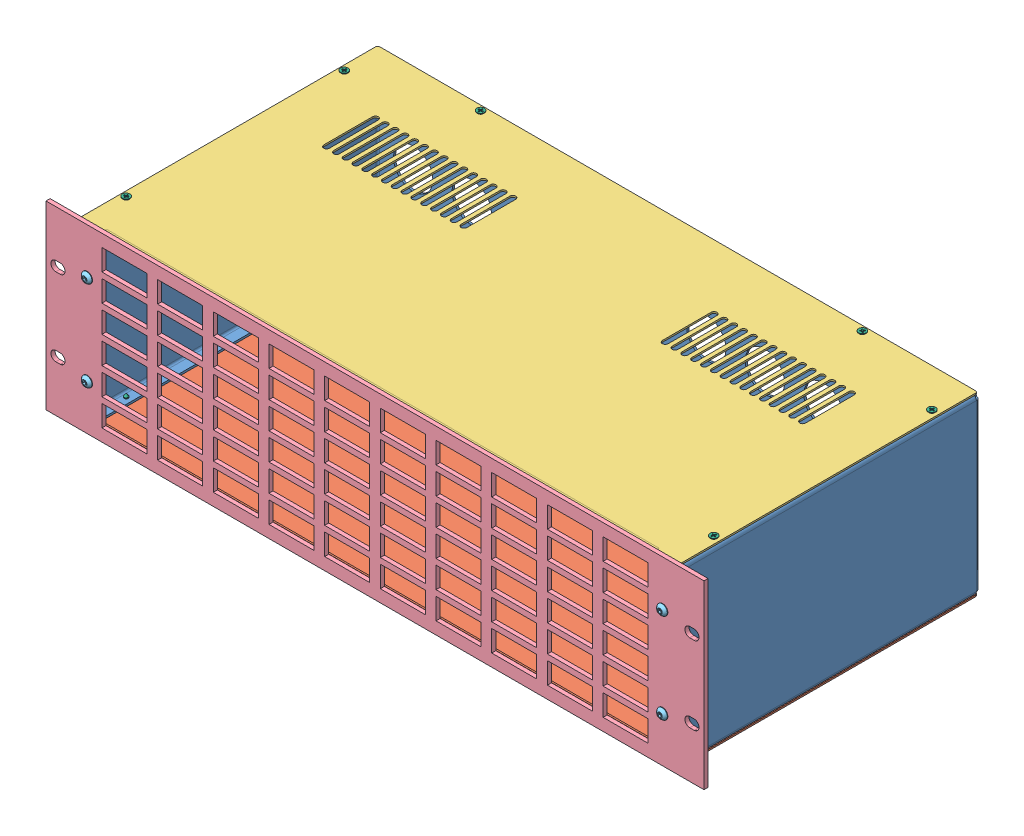
SolidWorks assembly Rack Wieland female, configuration R2100-3U. Lengths in mm.
Overall size (482.6 132.7 225.2).
20 component instances, 6 part files, 0 mates.
Components (placement in the parent):
- Frame 3U 10 presse-etoupes-1: Frame 3U 10 presse-etoupes [Défaut] at (0 0 -300) size (442 127 220)
- Penn Elcom-R2100-3U_R2100-R2110-Top-Base(R2100-005)-1: Penn Elcom-R2100-3U_R2100-R2110-Top-Base(R2100-005) [Default] at (0 -63.5 -80) x (-1 0 0) z (0 0 1) size (440 7.5 219)
- Penn Elcom-R2100-3U_R2100-R2110-Top-Base(R2100-006)-1: Penn Elcom-R2100-3U_R2100-R2110-Top-Base(R2100-006) [Default] at (0 63.5 -80) size (440 7.5 219)
- Rack 3U front panel 60x wieland female-1: Rack 3U front panel 60x wieland female [Default] at (0 0 -80) size (482.6 132.7 3)
- Penn Elcom-R2100-3U_02-012-10 (M4 x 10 Button Head)(02-012-10)-1: Penn Elcom-R2100-3U_02-012-10 (M4 x 10 Button Head)(02-012-10) [Default] at (211 -33 -74.8) x (0 0 -1) z (1 0 0) size (12.2 7.6 7.6)
- Penn Elcom-R2100-3U_02-012-10 (M4 x 10 Button Head)(02-012-10)-2: Penn Elcom-R2100-3U_02-012-10 (M4 x 10 Button Head)(02-012-10) [Default] at (211 33 -74.8) x (0 0 -1) z (1 0 0) size (12.2 7.6 7.6)
- Penn Elcom-R2100-3U_02-012-10 (M4 x 10 Button Head)(02-012-10)-3: Penn Elcom-R2100-3U_02-012-10 (M4 x 10 Button Head)(02-012-10) [Default] at (-211 33 -74.8) x (0 0 -1) z (1 0 0) size (12.2 7.6 7.6)
- Penn Elcom-R2100-3U_02-012-10 (M4 x 10 Button Head)(02-012-10)-4: Penn Elcom-R2100-3U_02-012-10 (M4 x 10 Button Head)(02-012-10) [Default] at (-211 -33 -74.8) x (0 0 -1) z (1 0 0) size (12.2 7.6 7.6)
- Penn Elcom-R2100-3U_01-023-10 (No4x6 CSK)-1: Penn Elcom-R2100-3U_01-023-10 (No4x6 CSK) [Default] at (-140 -65.85 -294.5) x (0 1 0) z (0 0 1) size (6.51 5.5 5.5)
- Penn Elcom-R2100-3U_01-023-10 (No4x6 CSK)-2: Penn Elcom-R2100-3U_01-023-10 (No4x6 CSK) [Default] at (215.5 -65.85 -270) x (0 1 0) z (0 0 1) size (6.51 5.5 5.5)
- Penn Elcom-R2100-3U_01-023-10 (No4x6 CSK)-3: Penn Elcom-R2100-3U_01-023-10 (No4x6 CSK) [Default] at (-215.5 65.85 -110) x (0 -1 0) z (0.087154 0 0.996195) size (6.51 5.5 5.5)
- Penn Elcom-R2100-3U_01-023-10 (No4x6 CSK)-4: Penn Elcom-R2100-3U_01-023-10 (No4x6 CSK) [Default] at (-215.5 65.85 -270) x (0 -1 0) z (0 0 1) size (6.51 5.5 5.5)
- Penn Elcom-R2100-3U_01-023-10 (No4x6 CSK)-5: Penn Elcom-R2100-3U_01-023-10 (No4x6 CSK) [Default] at (-215.5 -65.85 -110) x (0 1 0) z (0 0 1) size (6.51 5.5 5.5)
- Penn Elcom-R2100-3U_01-023-10 (No4x6 CSK)-6: Penn Elcom-R2100-3U_01-023-10 (No4x6 CSK) [Default] at (140 -65.85 -294.5) x (0 1 0) z (0 0 1) size (6.51 5.5 5.5)
- Penn Elcom-R2100-3U_01-023-10 (No4x6 CSK)-7: Penn Elcom-R2100-3U_01-023-10 (No4x6 CSK) [Default] at (215.5 -65.85 -110) x (0 1 0) z (0.678508 0 0.734593) size (6.51 5.5 5.5)
- Penn Elcom-R2100-3U_01-023-10 (No4x6 CSK)-8: Penn Elcom-R2100-3U_01-023-10 (No4x6 CSK) [Default] at (-215.5 -65.85 -270) x (0 1 0) z (0 0 1) size (6.51 5.5 5.5)
- Penn Elcom-R2100-3U_01-023-10 (No4x6 CSK)-9: Penn Elcom-R2100-3U_01-023-10 (No4x6 CSK) [Default] at (215.5 65.85 -110) x (0 -1 0) z (-0.257325 0 0.966325) size (6.51 5.5 5.5)
- Penn Elcom-R2100-3U_01-023-10 (No4x6 CSK)-10: Penn Elcom-R2100-3U_01-023-10 (No4x6 CSK) [Default] at (215.5 65.85 -270) x (0 -1 0) z (0 0 1) size (6.51 5.5 5.5)
- Penn Elcom-R2100-3U_01-023-10 (No4x6 CSK)-11: Penn Elcom-R2100-3U_01-023-10 (No4x6 CSK) [Default] at (-140 65.85 -294.5) x (0 -1 0) z (0 0 1) size (6.51 5.5 5.5)
- Penn Elcom-R2100-3U_01-023-10 (No4x6 CSK)-12: Penn Elcom-R2100-3U_01-023-10 (No4x6 CSK) [Default] at (140 65.85 -294.5) x (0 -1 0) z (0.664633 0 -0.74717) size (6.51 5.5 5.5)
